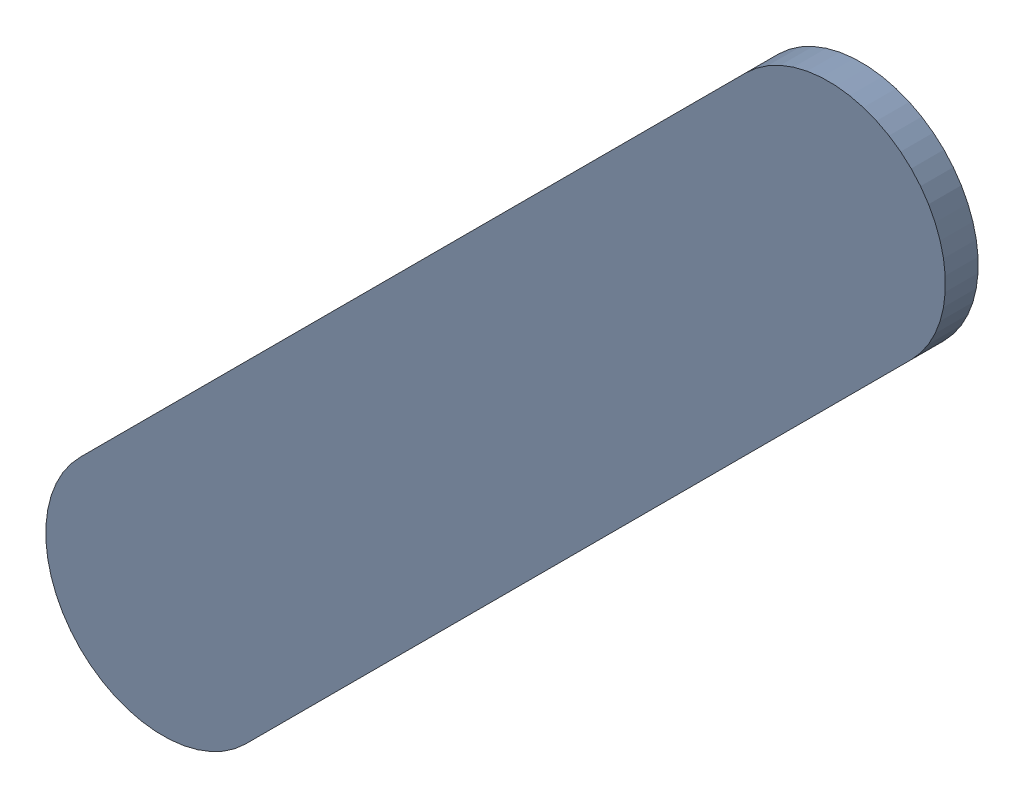
SolidWorks assembly Track (27.878mm,13.028mm)(28.6mm,13.75mm) on Top Layer, configuration Predeterminado. Lengths in mm.
Overall size (0.98 0.98 0.04).
2 component instances, 1 part files, 0 mates.
Components (placement in the parent):
- Track (27.878mm,13.028mm)(28.6mm,13.75mm) on Top Layer-1-1: Track (27.878mm,13.028mm)(28.6mm,13.75mm) on Top Layer-1 [Predeterminado] at (-68.317 -44.187 -0.0457) size (0.98 0.98 0.04)
  - Track (27.878mm,13.028mm)(28.6mm,13.75mm) on Top Layer-Part-1-1: Track (27.878mm,13.028mm)(28.6mm,13.75mm) on Top Layer-Part-1 [Predeterminado] at origin size (0.98 0.98 0.04)
